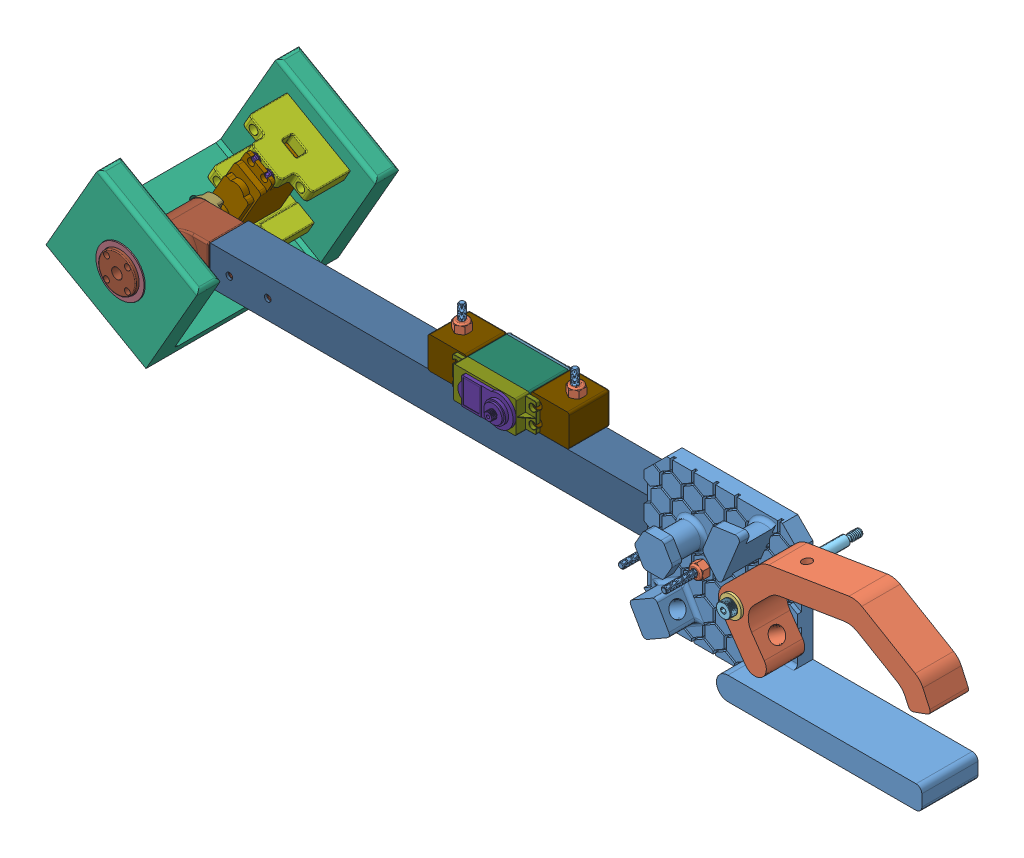
SolidWorks assembly MS-A-0013-01-Gripper, configuration Default. Lengths in mm.
Overall size (594.07 389.31 137.7).
42 component instances, 21 part files, 22 mates.
Components (placement in the parent):
- MS-A-0013c-Gripper Hand-1: MS-A-0013c-Gripper Hand [Default] at (121.9178 22.2802 -13.3162) size (217.31 157.41 91.11) (flexible)
  - MS-P-0051-Gripper Hand Back Panel-1: MS-P-0051-Gripper Hand Back Panel [Default] at (-64.4091 18.8681 157.7425) x (0 0 1) z (-1 0 0) size (37.15 100.98 210.82)
  - MS-P-0053-Gripper Hand Moving Finger-1: MS-P-0053-Gripper Hand Moving Finger [Default] at (17.8266 80.6815 159.33) x (0 0 1) z (-0.849272 0.527955 0) size (25.4 103.48 118.89)
  - 6389K406_LIGHT DUTY DRY-RUNNING SLEEVE BEARING-1: 6389K406_LIGHT DUTY DRY-RUNNING SLEEVE BEARING [6389K406] at (21.4092 80.3575 186.3175) x (-0.260924 -0.965359 0) z (0.965359 -0.260924 0) size (14.29 12.7 14.29)
  - 6389K406_LIGHT DUTY DRY-RUNNING SLEEVE BEARING-3: 6389K406_LIGHT DUTY DRY-RUNNING SLEEVE BEARING [6389K406] at (21.4092 80.3575 157.7425) x (-0.142341 0.989818 0) z (0.989818 0.142341 0) size (14.29 12.7 14.29)
  - 91831A029_TYPE 18-8 STAINLESS STL NYLON-INSERT LOCKNUT-1: 91831A029_TYPE 18-8 STAINLESS STL NYLON-INSERT LOCKNUT [91831A029] at (21.4092 80.3575 147.5825) x (0.82514 -0.564929 0) z (0.564929 0.82514 0) size (11.11 8.13 12.83)
  - 90298A552_18-8 STAINLESS STEEL SHOULDER SCREW-1: 90298A552_18-8 STAINLESS STEEL SHOULDER SCREW [90298A552] at (21.4092 80.3575 191.08) x (0.30218 -0.953251 0) z (0 0 1) size (9.53 9.53 91.11)
- MS-A-0013d-Gripper Arm-1: MS-A-0013d-Gripper Arm [Default] at (-270.9381 106.7898 113.9327) x (-0.868018 0.496532 0) z (0 0 1) size (382.14 221.38 129.64) (flexible)
  - MS-P-0057-Gripper Arm Mount Version1-1: MS-P-0057-Gripper Arm Mount Version1 [Default] at (-52.2477 40.78 53.3156) x (0 0 1) z (0 1 0) size (127 76.2 82.55)
  - MS-A-0013e-Shoulder Servo Mount Assembly-1: MS-A-0013e-Shoulder Servo Mount Assembly [Default] at (33.7787 -2.1863 -39.671) x (1 0 0) z (0 -1 0) size (48.26 52.81 57.28)
    - MS-P-0056-Shoulder Servo Mount-6: MS-P-0056-Shoulder Servo Mount [Default] at (-47.9263 -13.6934 17.7337) x (-1 0 0) z (0 1 0) size (48.26 9.14 35.05)
    - MS-P-0056-Shoulder Servo Mount-7: MS-P-0056-Shoulder Servo Mount [Default] at (-47.9263 -13.6934 -30.2663) x (1 0 0) z (0 1 0) size (48.26 9.14 35.05)
    - 97171A170_ HEAT-SET INSERT FOR PLASTIC-1: 97171A170_ HEAT-SET INSERT FOR PLASTIC [97171A170] at (-65.7063 -7.191 17.7337) x (0.915319 0 -0.402729) z (-0.402729 0 -0.915319) size (7.14 9.57 7.14)
    - 97171A170_ HEAT-SET INSERT FOR PLASTIC-2: 97171A170_ HEAT-SET INSERT FOR PLASTIC [97171A170] at (-30.1463 -7.191 17.7337) x (1 0 0) z (0 0 -1) size (7.14 9.57 7.14)
    - 97171A170_ HEAT-SET INSERT FOR PLASTIC-4: 97171A170_ HEAT-SET INSERT FOR PLASTIC [97171A170] at (-30.1463 -7.191 -30.2663) x (-1 0 0) z (0 0 1) size (7.14 9.57 7.14)
    - 97171A170_ HEAT-SET INSERT FOR PLASTIC-6: 97171A170_ HEAT-SET INSERT FOR PLASTIC [97171A170] at (-65.7063 -7.191 -30.2663) x (1 0 0) z (0 0 -1) size (7.14 9.57 7.14)
    - 97171A170_ HEAT-SET INSERT FOR PLASTIC-7: 97171A170_ HEAT-SET INSERT FOR PLASTIC [97171A170] at (-42.8463 8.1252 -30.2663) x (0.999861 0 -0.016687) z (0.016687 0 0.999861) size (7.14 9.57 7.14)
    - 97171A170_ HEAT-SET INSERT FOR PLASTIC-8: 97171A170_ HEAT-SET INSERT FOR PLASTIC [97171A170] at (-53.0063 8.1252 -30.2663) size (7.14 9.57 7.14)
    - 97171A170_ HEAT-SET INSERT FOR PLASTIC-9: 97171A170_ HEAT-SET INSERT FOR PLASTIC [97171A170] at (-42.8463 8.1252 17.7337) size (7.14 9.57 7.14)
    - 97171A170_ HEAT-SET INSERT FOR PLASTIC-10: 97171A170_ HEAT-SET INSERT FOR PLASTIC [97171A170] at (-53.0063 8.1252 17.7337) size (7.14 9.57 7.14)
    - MS-C-0032-Gripper Shoulder Servo-1: MS-C-0032-Gripper Shoulder Servo [Default] at (-48.0063 17.0406 -6.2663) x (0 0 -1) z (1 0 0) size (53.2 43.5 20)
  - MS-P-0054-Box Tubing-1: MS-P-0054-Box Tubing [Default] at (-36.8265 1.1528 7.6336) x (0 0 -1) z (-0.868018 -0.496532 0) size (25.4 25.4 355.6)
  - MS-P-0058-Shoulder L Joint-1: MS-P-0058-Shoulder L Joint [Default] at (-14.2277 14.08 8.3321) x (0 0 -1) z (-0.868018 -0.496532 0) size (58.74 26.61 88.65)
  - 525130.step-1: 525130.step [Default] at (-14.2277 14.08 -9.1304) x (0.496532 -0.868018 0) z (-0.868018 -0.496532 0) size (25.39 6.35 25.39)
  - MS-C-0028-Servo Arm Bushing-1: MS-C-0028-Servo Arm Bushing [2934T25] at (-14.2277 14.08 34.9006) x (1 0 0) z (0 -1 0) size (38.1 19.05 38.1)
- Part1^MS-A-0013-01-Gripper-1: Part1^MS-A-0013-01-Gripper [Default] at origin (virtual)
- MS-A-0013a-Hand Servo Mount Assembly-2: MS-A-0013a-Hand Servo Mount Assembly [Default] at (-67.2669 124.9959 74.1416) x (0 1 0) z (1 0 0) size (21.09 45.49 92.36)
  - 11886-2: 11886 [Default] at (-16.5206 37.1922 18.007) size (21 45.43 55.5)
    - 11886_bottom-1: 11886_bottom [Default] at (2.2223 -4.2785 0.9275) size (21 2.43 41.5)
    - 11886_middle-1: 11886_middle [Default] at (2.2223 -1.8785 0.9275) size (21 25.7 42.9)
    - 11886_upper-1: 11886_upper [Default] at (6.1473 23.8215 -5.3225) size (21 8.72 55.5)
    - 11886_top-1: 11886_top [Default] at (2.2223 32.5215 0.7275) size (20 8.6 36.5)
  - MS-P-0055-Hand Servo Mount-1: MS-P-0055-Hand Servo Mount [Default] at (-14.2513 32.8197 52.4125) x (0 0 1) z (-1 0 0) size (25.4 27.18 21.08)
  - MS-P-0055-Hand Servo Mount-2: MS-P-0055-Hand Servo Mount [Default] at (-14.2513 33.8357 -14.5435) x (0 0 -1) z (1 0 0) size (25.4 27.18 21.08)
- 92196A178_18-8 STAINLESS STEEL SOCKET HEAD SCREW-1: 92196A178_18-8 STAINLESS STEEL SOCKET HEAD SCREW [92196A178] at (-10.9443 136.7161 121.5663) x (0.998783 0 0.049324) z (0 1 0) size (6.85 6.85 42.92)
- 92196A178_18-8 STAINLESS STEEL SOCKET HEAD SCREW-2: 92196A178_18-8 STAINLESS STEEL SOCKET HEAD SCREW [92196A178] at (-85.6203 136.7161 121.5663) x (0.067769 0 -0.997701) z (0 1 0) size (6.85 6.85 42.92)
- 90631A009_LOW-STRENGTH STEEL NYLON-INSERT LOCKNUT-2: 90631A009_LOW-STRENGTH STEEL NYLON-INSERT LOCKNUT [90631A009] at (-85.6203 121.2856 121.5663) size (8.73 6.09 10.08)
- 90631A009_LOW-STRENGTH STEEL NYLON-INSERT LOCKNUT-3: 90631A009_LOW-STRENGTH STEEL NYLON-INSERT LOCKNUT [90631A009] at (-11.0443 121.2856 120.5503) size (8.73 6.09 10.08)
- 92196A178_18-8 STAINLESS STEEL SOCKET HEAD SCREW-5: 92196A178_18-8 STAINLESS STEEL SOCKET HEAD SCREW [92196A178] at (97.0057 87.5036 170.7788) x (0.90391 -0.427722 0) z (0 0 1) size (6.85 6.85 42.92)
- 92196A178_18-8 STAINLESS STEEL SOCKET HEAD SCREW-6: 92196A178_18-8 STAINLESS STEEL SOCKET HEAD SCREW [92196A178] at (68.5577 87.5036 170.7788) x (0.267192 0.963643 0) z (0 0 1) size (6.85 6.85 42.92)
- 90631A009_LOW-STRENGTH STEEL NYLON-INSERT LOCKNUT-4: 90631A009_LOW-STRENGTH STEEL NYLON-INSERT LOCKNUT [90631A009] at (68.5577 87.5036 144.4263) x (1 0 0) z (0 -1 0) size (8.73 6.09 10.08)
- 90631A009_LOW-STRENGTH STEEL NYLON-INSERT LOCKNUT-5: 90631A009_LOW-STRENGTH STEEL NYLON-INSERT LOCKNUT [90631A009] at (97.0057 87.5036 144.4263) x (1 0 0) z (0 -1 0) size (8.73 6.09 10.08)
Mates (geometry in assembly coordinates):
- Parallel1: parallel aligned: plane of GripperArmAssembly-1/GripperArmBoxTubing-1 through (116.0557 100.2036 108.8663) normal (0 0 -1); plane of GripperClawServoMount-2/ClawServoSideMount-1 through (-14.8543 110.7446 106.9613) normal (0 0 -1)
- Concentric3: concentric anti-aligned: circle of GripperArmAssembly-1/GripperArmBoxTubing-1; circle of GripperClawServoMount-2/ClawServoSideMount-2
- Coincident13: coincident anti-aligned: plane of Gripper-1/BackPanel-1 through (57.5087 41.1483 134.2663) normal (0 0 -1); plane of GripperArmAssembly-1/GripperArmBoxTubing-1 through (116.0557 100.2036 134.2663) normal (0 0 1)
- Coincident14: coincident anti-aligned: plane of GripperArmAssembly-1/GripperArmBoxTubing-1 through (116.0557 100.2036 134.2663) normal (0 1 0); plane of GripperClawServoMount-2/ClawServoSideMount-2 through (-69.1103 100.2036 135.1553) normal (0 -1 0)
- Concentric6: concentric aligned: circle of GripperArmAssembly-1/GripperArmBoxTubing-1; circle of 92196A178_18-8 STAINLESS STEEL SOCKET HEAD SCREW-2
- Concentric7: concentric aligned: circle of GripperArmAssembly-1/GripperArmBoxTubing-1; circle of 92196A178_18-8 STAINLESS STEEL SOCKET HEAD SCREW-1
- Coincident15: coincident anti-aligned: plane of GripperArmAssembly-1/GripperArmBoxTubing-1 through (116.0557 98.6161 132.6788) normal (0 -1 0); plane of 92196A178_18-8 STAINLESS STEEL SOCKET HEAD SCREW-2 through (-85.6203 98.6161 121.5663) normal (0 1 0)
- Concentric8: concentric anti-aligned: circle of GripperClawServoMount-2/ClawServoSideMount-2; circle of 90631A009_LOW-STRENGTH STEEL NYLON-INSERT LOCKNUT-2
- Coincident16: coincident anti-aligned: plane of GripperClawServoMount-2/ClawServoSideMount-2 through (-69.1103 121.2856 135.1553) normal (0 1 0); plane of 90631A009_LOW-STRENGTH STEEL NYLON-INSERT LOCKNUT-2 through (-89.986 121.2856 114.0049) normal (0 -1 0)
- Concentric9: concentric aligned: circle of GripperClawServoMount-2/ClawServoSideMount-1; circle of 90631A009_LOW-STRENGTH STEEL NYLON-INSERT LOCKNUT-3
- Coincident17: coincident anti-aligned: plane of GripperClawServoMount-2/ClawServoSideMount-1 through (-27.5543 121.2856 134.1393) normal (0 1 0); plane of 90631A009_LOW-STRENGTH STEEL NYLON-INSERT LOCKNUT-3 through (-15.41 121.2856 112.9889) normal (0 -1 0)
- Concentric10: concentric aligned: circle of Gripper-1/BackPanel-1; circle of GripperArmAssembly-1/GripperArmBoxTubing-1
- Concentric11: concentric anti-aligned: circle of Gripper-1/BackPanel-1; circle of GripperArmAssembly-1/GripperArmBoxTubing-1
- Concentric14: concentric aligned: circle of GripperArmAssembly-1/GripperArmBoxTubing-1; circle of 92196A178_18-8 STAINLESS STEEL SOCKET HEAD SCREW-6
- Concentric15: concentric aligned: circle of GripperArmAssembly-1/GripperArmBoxTubing-1; circle of 92196A178_18-8 STAINLESS STEEL SOCKET HEAD SCREW-5
- Coincident21: coincident anti-aligned: plane of GripperArmAssembly-1/GripperArmBoxTubing-1 through (116.0557 98.6161 132.6788) normal (0 0 -1); plane of 92196A178_18-8 STAINLESS STEEL SOCKET HEAD SCREW-6 through (68.5577 87.5036 132.6788) normal (0 0 1)
- Coincident24: coincident anti-aligned: plane of GripperArmAssembly-1/GripperArmBoxTubing-1 through (116.0557 98.6161 132.6788) normal (0 0 -1); plane of 92196A178_18-8 STAINLESS STEEL SOCKET HEAD SCREW-5 through (97.0057 87.5036 132.6788) normal (0 0 1)
- Concentric16: concentric aligned: circle of Gripper-1/BackPanel-1; circle of 90631A009_LOW-STRENGTH STEEL NYLON-INSERT LOCKNUT-4
- Coincident25: coincident anti-aligned: plane of Gripper-1/BackPanel-1 through (57.5087 41.1483 144.4263) normal (0 0 1); plane of 90631A009_LOW-STRENGTH STEEL NYLON-INSERT LOCKNUT-4 through (64.192 95.0651 144.4263) normal (0 0 -1)
- Concentric17: concentric aligned: circle of Gripper-1/BackPanel-1; circle of 90631A009_LOW-STRENGTH STEEL NYLON-INSERT LOCKNUT-5
- Coincident26: coincident anti-aligned: plane of Gripper-1/BackPanel-1 through (57.5087 41.1483 144.4263) normal (0 0 1); plane of 90631A009_LOW-STRENGTH STEEL NYLON-INSERT LOCKNUT-5 through (92.64 95.0651 144.4263) normal (0 0 -1)
- Coincident27: coincident anti-aligned: plane of GripperArmAssembly-1/GripperArmBoxTubing-1 through (116.0557 98.6161 132.6788) normal (0 -1 0); plane of 92196A178_18-8 STAINLESS STEEL SOCKET HEAD SCREW-1 through (-10.9443 98.6161 121.5663) normal (0 1 0)
